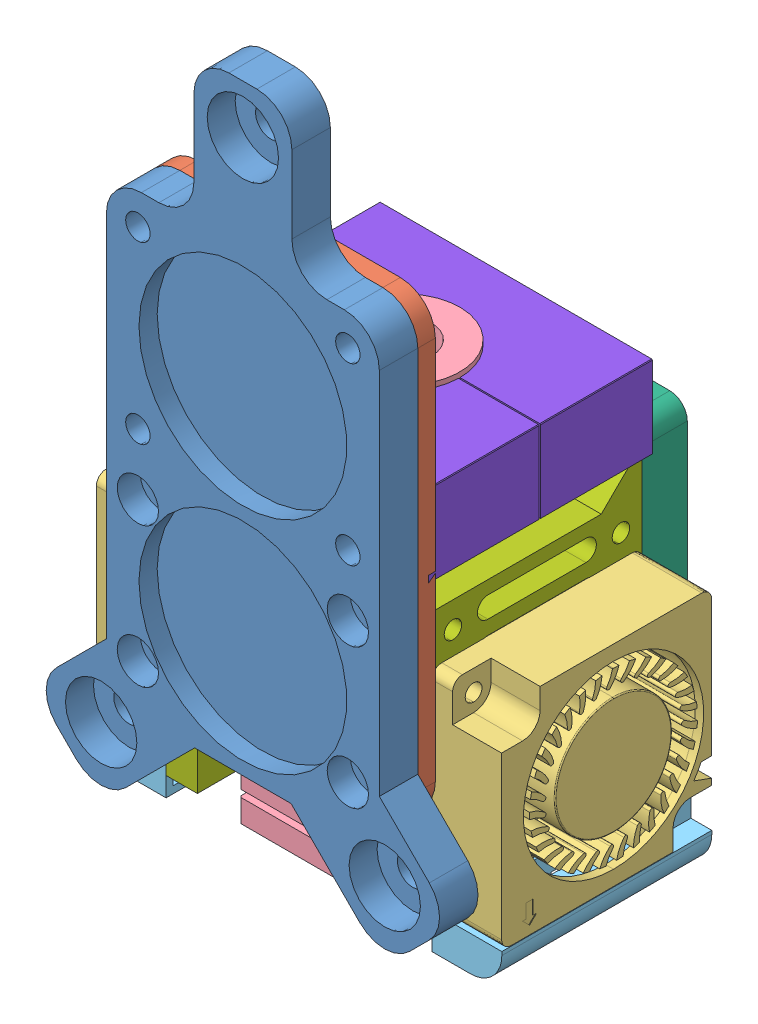
SolidWorks assembly Toolchanger_v3, configuration Default. Lengths in mm.
Overall size (56.2 99.41 39.01).
12 component instances, 8 part files, 9 mates.
Components (placement in the parent):
- tool_changer_v2_tool-1: tool_changer_v2_tool [Default] at (21.2596 28.9247 93.0438) size (56.2 97.27 5.5)
- Part5^Toolchanger_v3-1: Part5^Toolchanger_v3 [Default] at (21.2596 28.9247 86.5438) x (-1 0 0) z (0 0 -1) size (39 64.9 2.5) (virtual)
- E3Dv6_PRO_3010-2: E3Dv6_PRO_3010 [Default] at (42.9854 37.0108 69.0297) x (0 0 -1) z (0 1 0) size (30 38 43.1)
  - E3Dv6_PRO_3010.stp-1: E3Dv6_PRO_3010.stp [Default] at origin size (40.99 58 61.3)
    - ________-3010.stp-1: ________-3010.stp [Default] at (1 2.7759 -25) x (0 0 -1) z (0 -1 0) size (30 30 10)
    - ____-E3Dv6.stp-1: ____-E3Dv6.stp [Default] at (0 21.7259 -37.3574) x (0 1 0) z (0 0 1) size (22.3 26.65 61.3)
    - ________-3010.stp-2: ________-3010.stp [Default] at (-1 40.6759 -25) x (0 0 -1) z (0 1 0) size (30 30 10)
    - ______-3010.stp-1: ______-3010.stp [Default] at origin size (30 10 10)
    - ______-3010.stp-2: ______-3010.stp [Default] at (0 43.4517 0) x (-1 0 0) z (0 0 1) size (30 10 10)
    - ________-3010-0.stp-1: ________-3010-0.stp [Default] at (25.4859 21.7259 -10.1259) x (0 1 0) z (-1 0 0) size (30 30.54 10.5)
    - E3Dv6_______3010.stp-1: E3Dv6_______3010.stp [Default] at origin size (30 38 43.1)
- v6_clamp-1: v6_clamp [Výchozí] at (28.7596 54.0034 66.9481) x (0 0 -1) z (0 -1 0) size (32 39 11.7)
Mates (geometry in assembly coordinates):
- InPlace1: in place: plane of tool_changer_v2_tool-1 through (21.2596 28.9247 86.5438) normal (0 0 -1); plane of ? through (0 0 86.5438) normal (0 0 -1); moOrthogonalPlaneRef_w of tool_changer_v2_tool-1 through (21.2596 28.9247 86.5438) normal (0 0 -1); plane of ? through (0 0 86.5438) normal (0 1 0); plane of tool_changer_v2_tool-1 through (21.2596 28.9247 86.5438) normal (0 0 -1); plane of ? through (0 0 86.5438) normal (-1 0 0); plane of tool_changer_v2_tool-1 through (21.2596 28.9247 86.5438) normal (0 0 -1); unknown of Part5^Toolchanger_v3-1
- Coincident1: coincident aligned: plane of ?; plane of ?
- Coincident2: coincident aligned: moOrthogonalPlaneRef_w of tool_changer_v2_tool-1 through (21.2596 28.9247 86.5438) normal (0 1 0); plane of Part5^Toolchanger_v3-1 through (21.2596 28.9247 86.5438) normal (0 1 0)
- Coincident3: coincident anti-aligned: moOrthogonalPlaneRef_w of tool_changer_v2_tool-1 through (21.2596 28.9247 86.5438) normal (1 0 0); plane of Part5^Toolchanger_v3-1 through (21.2596 28.9247 86.5438) normal (-1 0 0)
- Width1: width anti-aligned: plane of E3Dv6_PRO_3010-2/E3Dv6_PRO_3010.stp-1/E3Dv6_______3010.stp-1 through (2.2596 19.6472 61.8061) normal (-1 0 0); plane of Part5^Toolchanger_v3-1 through (40.2596 19.6472 61.8061) normal (1 0 0); plane of E3Dv6_PRO_3010-2/E3Dv6_PRO_3010.stp-1/E3Dv6_______3010.stp-1 through (40.7596 17.2413 84.0438) normal (1 0 0); plane of Part5^Toolchanger_v3-1 through (1.7596 72.1413 84.0438) normal (-1 0 0)
- Coincident12: coincident anti-aligned: plane of Part5^Toolchanger_v3-1 through (35.7596 72.1413 84.0438) normal (0 0 -1); plane of E3Dv6_PRO_3010-2/E3Dv6_PRO_3010.stp-1/E3Dv6_______3010.stp-1 through (4.5096 18.3942 84.0438) normal (0 0 1)
- Concentric1: concentric anti-aligned: cylinder of E3Dv6_PRO_3010-2/E3Dv6_PRO_3010.stp-1/____-E3Dv6.stp-1 through (21.2596 51.0034 69.0297) axis (0 -1 0) radius 6; cylinder of v6_clamp-1 through (21.2596 41.3034 69.0297) axis (0 1 0) radius 6
- Parallel3: parallel aligned: plane of Part5^Toolchanger_v3-1 through (40.7596 17.2413 84.0438) normal (1 0 0); plane of v6_clamp-1 through (40.7596 41.3034 66.9481) normal (1 0 0)
- Coincident14: coincident anti-aligned: plane of E3Dv6_PRO_3010-2/E3Dv6_PRO_3010.stp-1/____-E3Dv6.stp-1 through (19.5988 45.0034 61.204) normal (0 1 0); plane of v6_clamp-1 through (21.2596 45.0034 69.0297) normal (0 -1 0)
